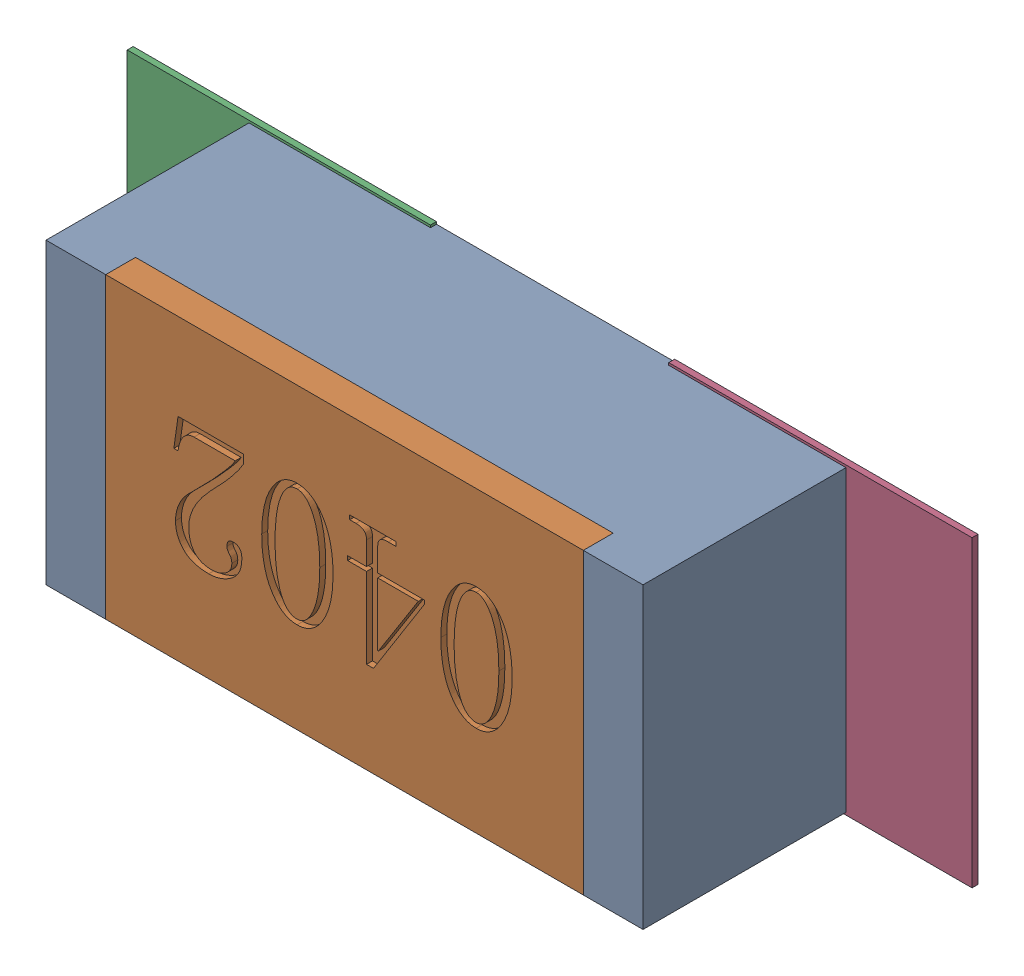
SolidWorks assembly R25, configuration Défaut. Lengths in mm.
Overall size (1.42 0.51 0.35).
5 component instances, 2 part files, 0 mates.
Components (placement in the parent):
- R0402-1: R0402 [Défaut] at (20.0335 -29.0363 0) x (-1 0 0) z (0 0 1) size (1 0.5 0.35)
- 6504207776-1: 6504207776 [Défaut] at (19.5835 -29.0365 0) size (0.51 0.51 0.01)
  - Extruded-1: Extruded [Défaut] at origin size (0.51 0.51 0.01)
- 6504207776-2: 6504207776 [Défaut] at (20.4906 -29.0365 0) size (0.51 0.51 0.01)
  - Extruded-1: Extruded [Défaut] at origin size (0.51 0.51 0.01)
